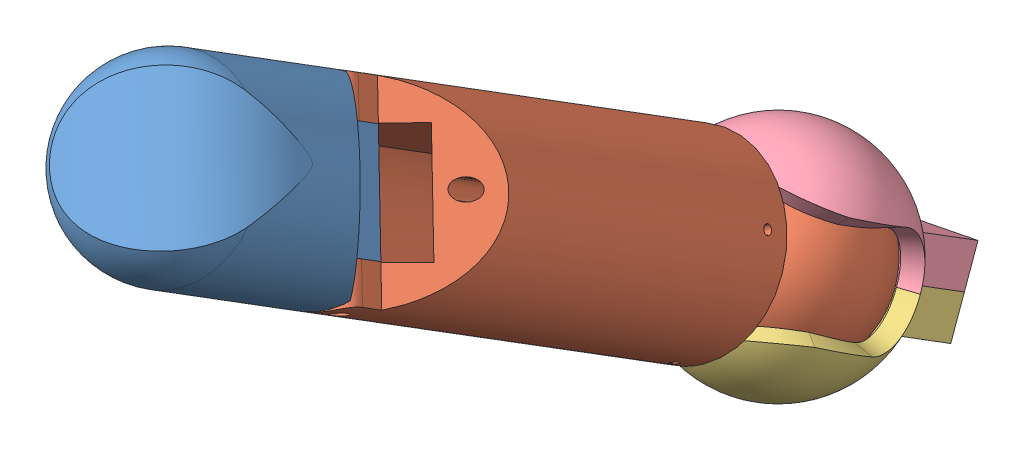
SolidWorks assembly ThumbAssembly, configuration Default. Lengths in mm.
Overall size (24.84 62.95 83.3).
4 component instances, 4 part files, 11 mates.
Components (placement in the parent):
- Resized_TipDigit_Mid-1: Resized_TipDigit_Mid [Default] at (31.6152 29.016 26.2641) x (0.039241 -0.519455 -0.853596) z (0.868647 0.439954 -0.2278) size (25.82 16 16)
- Resized_BaseDigit_Mid-1: Resized_BaseDigit_Mid [Default] at (32.4513 15.4119 4.11) x (0.039241 -0.519455 -0.853596) z (-0.493875 0.732535 -0.468487) size (55.19 16 16)
- Resized_Balljoint_socket_L-1: Resized_Balljoint_socket_L [Default] at (34.0231 -3.2273 -28.7523) x (-0.15904 0.840118 -0.518564) z (0.986492 0.156105 -0.049647) size (9.96 22.72 18.45)
- Resized_Balljoint_socket_R-1: Resized_Balljoint_socket_R [Default] at (34.3788 -5.101 -27.5926) x (-0.15904 0.840118 -0.518564) z (0.986492 0.156105 -0.049647) size (9.98 22.72 18.51)
Mates (geometry in assembly coordinates):
- Concentric1: concentric anti-aligned: circle of Resized_Balljoint_socket_L-1; circle of Resized_Balljoint_socket_R-1
- Coincident2: coincident anti-aligned: plane of Resized_Balljoint_socket_L-1 through (34.0111 -4.6669 -28.9288) normal (-0.15904 0.840118 -0.518564); plane of Resized_Balljoint_socket_R-1 through (34.0111 -4.6669 -28.9288) normal (0.15904 -0.840118 0.518564)
- Concentric2: concentric: sphere of Resized_Balljoint_socket_L-1; sphere of Resized_Balljoint_socket_R-1
- Coincident3: coincident anti-aligned: plane of ? through (30.3879 -10.2032 -43.5332) normal (0.15904 -0.840118 0.518564); plane of Resized_Balljoint_socket_R-1 through (30.3175 -6.4295 -37.398) normal (-0.15904 0.840118 -0.518564)
- Coincident4: coincident anti-aligned: plane of ? through (38.6493 -15.1362 -40.1515) normal (-0.986492 -0.156105 0.049647); plane of Resized_Balljoint_socket_L-1 through (38.3326 -11.2154 -34.1171) normal (0.986492 0.156105 -0.049647)
- Coincident5: coincident anti-aligned: plane of ? through (50.4499 -11.5617 -41.7843) normal (-0.039241 0.519455 0.853596); plane of Resized_Balljoint_socket_L-1 through (34.6076 -12.5626 -41.9034) normal (0.039241 -0.519455 -0.853596)
- Concentric3: concentric: sphere of Resized_BaseDigit_Mid-1; sphere of Resized_Balljoint_socket_L-1
- Concentric4: concentric anti-aligned: circle of Resized_TipDigit_Mid-1; circle of Resized_BaseDigit_Mid-1
- Concentric5: concentric aligned: cylinder of Resized_TipDigit_Mid-1 through (32.1631 19.7959 11.2697) axis (-0.039241 0.519455 0.853596) radius 8; cylinder of Resized_BaseDigit_Mid-1 through (33.4727 2.4601 -17.2174) axis (-0.039241 0.519455 0.853596) radius 8
- Perpendicular1: perpendicular: plane of ? through (35.9069 0.4628 -41.804) normal (-0.039241 0.519455 0.853596); plane of Resized_BaseDigit_Mid-1 through (29.0378 -10.2677 -35.0049) normal (-0.868647 -0.439954 0.2278)
- Parallel2: parallel aligned: plane of ? through (43.8456 -17.0187 -77.5072) normal (-0.493875 0.732535 -0.468487); plane of Resized_BaseDigit_Mid-1 through (31.8175 -8.8598 -35.7339) normal (-0.493875 0.732535 -0.468487)
